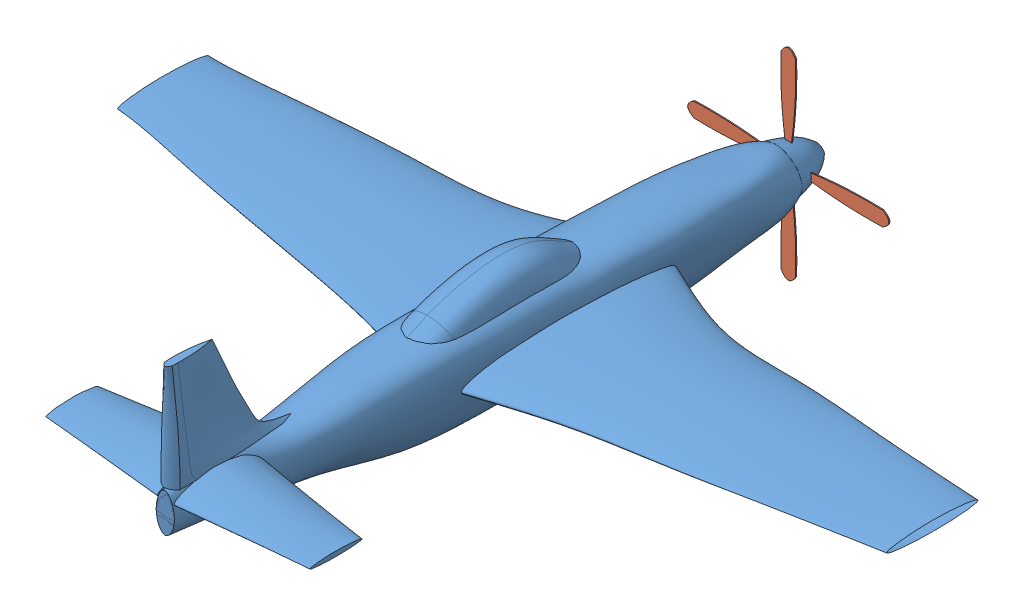
SolidWorks assembly Montaj1, configuration Varsayılan. Lengths in mm.
Overall size (703.29 217.63 597.78).
2 component instances, 2 part files, 0 mates.
Components (placement in the parent):
- uçak başla3-1: uçak başla3 [Varsayılan] at (448.8836 -61.1847 -505.4539) size (703.29 179.56 597.78)
- perv-1: perv [Varsayılan] at (447.9891 -14.6998 -966.2917) size (183.9 183.93 1)
